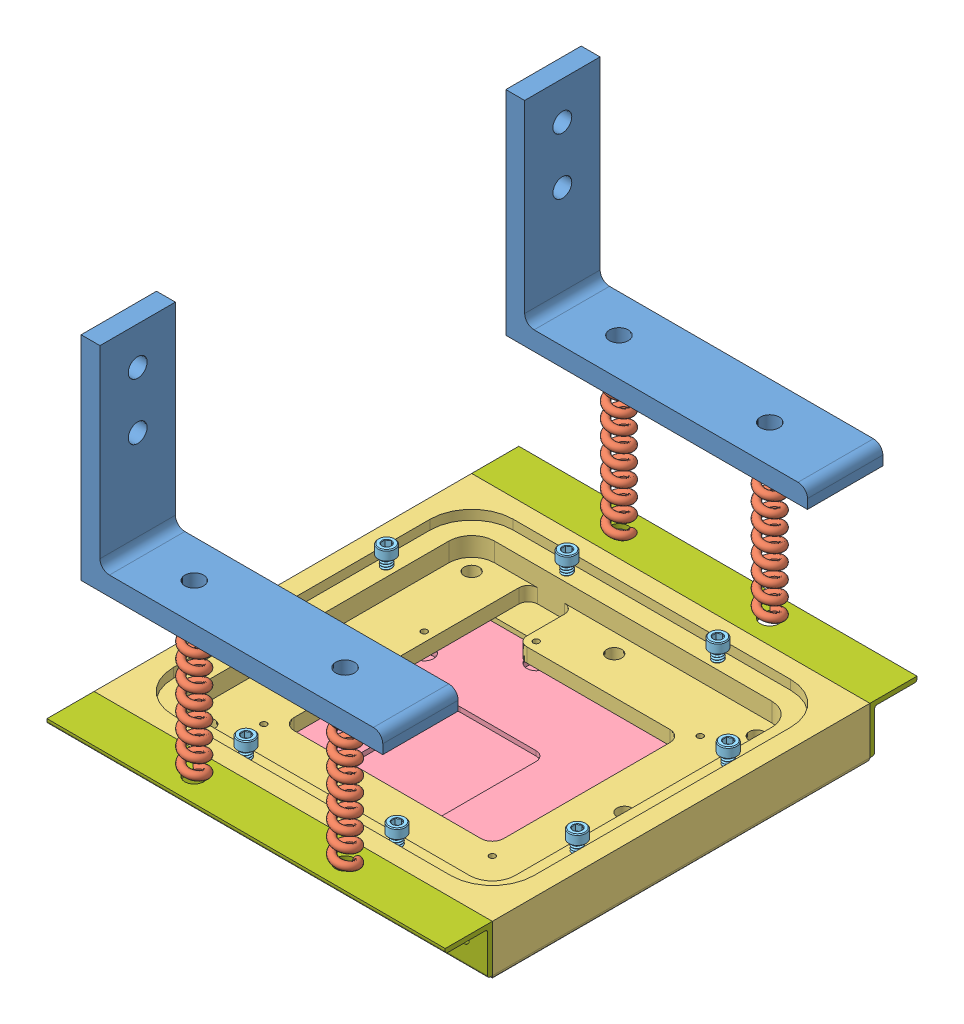
SolidWorks assembly SensorAssembly, configuration Default. Lengths in mm.
Overall size (134.11 141.53 168.43).
24 component instances, 8 part files, 20 mates.
Components (placement in the parent):
- Sensor Mount Bracket-1: Sensor Mount Bracket [8982K286] at (7.5304 42.6839 -62.5585) x (0 -1 0) z (0 0 1) size (71.68 101.6 25.4)
- Sensor Mount Bracket-2: Sensor Mount Bracket [8982K286] at (7.5304 42.6839 80.4689) x (0 -1 0) z (0 0 1) size (71.68 101.6 25.4)
- Rudimentary Spring-1: Rudimentary Spring [Default] at (32.9304 -46.2161 -62.5585) x (-0.173505 0 0.984833) z (-0.984833 0 -0.173505) size (9.2 55.29 9.2)
- Rudimentary Spring-2: Rudimentary Spring [Default] at (83.7304 -46.2161 -62.5585) x (0.992471 0 0.122483) z (-0.122483 0 0.992471) size (9.2 55.29 9.2)
- Rudimentary Spring-3: Rudimentary Spring [Default] at (32.9304 -46.2161 80.4689) size (9.2 55.29 9.2)
- Rudimentary Spring-4: Rudimentary Spring [Default] at (83.7304 -46.2161 80.4689) x (0.394048 0 0.91909) z (-0.91909 0 0.394048) size (9.2 55.29 9.2)
- NDE Sensor Mount Assembly-2: NDE Sensor Mount Assembly [Default] at (58.3304 -65.2661 8.9552) size (134.11 22.72 127.15)
  - CaseBody-1: CaseBody [Default] at origin size (134.11 17.46 127.15)
  - WearPlateAndMount-1: WearPlateAndMount [Default] at (0 3.175 0) size (108.71 3.17 101.75)
  - Cover Plate-1: Cover Plate [Default] at (0 15.875 0) size (121.41 3.17 114.45) (hidden)
  - 97334A146_NYLON SOCKET HEAD CAP SCREW-1: 97334A146_NYLON SOCKET HEAD CAP SCREW [97334A146] at (-57.531 9.525 -25.4) x (1 0 0) z (0 -1 0) size (5.74 5.74 13.88)
  - 97334A146_NYLON SOCKET HEAD CAP SCREW-2: 97334A146_NYLON SOCKET HEAD CAP SCREW [97334A146] at (-57.531 9.525 25.4) x (1 0 0) z (0 -1 0) size (5.74 5.74 13.88)
  - 97334A146_NYLON SOCKET HEAD CAP SCREW-3: 97334A146_NYLON SOCKET HEAD CAP SCREW [97334A146] at (-25.4 9.525 54.0512) x (1 0 0) z (0 -1 0) size (5.74 5.74 13.88)
  - 97334A146_NYLON SOCKET HEAD CAP SCREW-4: 97334A146_NYLON SOCKET HEAD CAP SCREW [97334A146] at (-25.4 9.525 -54.0512) x (1 0 0) z (0 -1 0) size (5.74 5.74 13.88)
  - 97334A146_NYLON SOCKET HEAD CAP SCREW-5: 97334A146_NYLON SOCKET HEAD CAP SCREW [97334A146] at (25.4 9.525 -54.0512) x (1 0 0) z (0 -1 0) size (5.74 5.74 13.88)
  - 97334A146_NYLON SOCKET HEAD CAP SCREW-6: 97334A146_NYLON SOCKET HEAD CAP SCREW [97334A146] at (25.4 9.525 54.0512) x (1 0 0) z (0 -1 0) size (5.74 5.74 13.88)
  - 97334A146_NYLON SOCKET HEAD CAP SCREW-7: 97334A146_NYLON SOCKET HEAD CAP SCREW [97334A146] at (57.531 9.525 -25.4) x (1 0 0) z (0 -1 0) size (5.74 5.74 13.88)
  - 97334A146_NYLON SOCKET HEAD CAP SCREW-8: 97334A146_NYLON SOCKET HEAD CAP SCREW [97334A146] at (57.531 9.525 25.4) x (1 0 0) z (0 -1 0) size (5.74 5.74 13.88)
- 97164A111_TAPEARED HEAT-SET INSERTS FOR PLASTIC -1: 97164A111_TAPEARED HEAT-SET INSERTS FOR PLASTIC  [97164A111] at (-0.7881 -54.1536 68.7214) x (1 0 0) z (0 -1 0) size (5.6 7.12 5.61)
- 97164A111_TAPEARED HEAT-SET INSERTS FOR PLASTIC -2: 97164A111_TAPEARED HEAT-SET INSERTS FOR PLASTIC  [97164A111] at (117.4489 -54.1536 68.7214) x (1 0 0) z (0 -1 0) size (5.6 7.12 5.61)
- 97164A111_TAPEARED HEAT-SET INSERTS FOR PLASTIC -3: 97164A111_TAPEARED HEAT-SET INSERTS FOR PLASTIC  [97164A111] at (-0.7881 -54.1536 -50.811) x (-0.923728 -0.383049 0) z (0.383049 -0.923728 0) size (5.6 7.12 5.61)
- 97164A111_TAPEARED HEAT-SET INSERTS FOR PLASTIC -4: 97164A111_TAPEARED HEAT-SET INSERTS FOR PLASTIC  [97164A111] at (117.4489 -54.1536 -50.811) x (-0.923728 -0.383049 0) z (0.383049 -0.923728 0) size (5.6 7.12 5.61)
- 8982K511_MULTIPURPOSE 6061 ALUMINUM 90 DEGREE ANGLE (1)-1: 8982K511_MULTIPURPOSE 6061 ALUMINUM 90 DEGREE ANGLE (1) [8982K511] at (58.3304 -54.1536 -54.621) x (0 1 0) z (-1 0 0) size (15.88 15.88 134.11)
- 8982K511_MULTIPURPOSE 6061 ALUMINUM 90 DEGREE ANGLE (1)-4: 8982K511_MULTIPURPOSE 6061 ALUMINUM 90 DEGREE ANGLE (1) [8982K511] at (58.3304 -54.1536 72.5314) x (0 1 0) z (1 0 0) size (15.88 15.88 134.11)
Mates (geometry in assembly coordinates):
- Coincident18: coincident anti-aligned: plane of Revised NDE Sensor Mount-1/CaseBody-1 through (-0.7881 -54.1536 66.1814) normal (0 0 1); plane of 97164A111_TAPEARED HEAT-SET INSERTS FOR PLASTIC -1 through (1.2947 -54.1536 66.1814) normal (0 0 -1)
- Concentric7: concentric aligned: circle of Revised NDE Sensor Mount-1/CaseBody-1; circle of 97164A111_TAPEARED HEAT-SET INSERTS FOR PLASTIC -1
- Coincident19: coincident anti-aligned: plane of Revised NDE Sensor Mount-1/CaseBody-1 through (-0.7881 -54.1536 -48.271) normal (0 0 -1); plane of 97164A111_TAPEARED HEAT-SET INSERTS FOR PLASTIC -3 through (-2.712 -54.9514 -48.271) normal (0 0 1)
- Concentric8: concentric aligned: cylinder of Revised NDE Sensor Mount-1/CaseBody-1 through (-0.7881 -54.1536 -48.271) axis (0 0 -1) radius 2.3495; circle of 97164A111_TAPEARED HEAT-SET INSERTS FOR PLASTIC -3
- Coincident20: coincident anti-aligned: plane of Revised NDE Sensor Mount-1/CaseBody-1 through (117.4489 -54.1536 -48.271) normal (0 0 -1); plane of 97164A111_TAPEARED HEAT-SET INSERTS FOR PLASTIC -4 through (115.525 -54.9514 -48.271) normal (0 0 1)
- Concentric9: concentric aligned: cylinder of Revised NDE Sensor Mount-1/CaseBody-1 through (117.4489 -54.1536 -48.271) axis (0 0 -1) radius 2.3495; circle of 97164A111_TAPEARED HEAT-SET INSERTS FOR PLASTIC -4
- Coincident21: coincident anti-aligned: plane of Revised NDE Sensor Mount-1/CaseBody-1 through (117.4489 -54.1536 66.1814) normal (0 0 1); plane of 97164A111_TAPEARED HEAT-SET INSERTS FOR PLASTIC -2 through (119.5317 -54.1536 66.1814) normal (0 0 -1)
- Concentric10: concentric aligned: cylinder of Revised NDE Sensor Mount-1/CaseBody-1 through (117.4489 -54.1536 66.1814) axis (0 0 1) radius 2.3495; circle of 97164A111_TAPEARED HEAT-SET INSERTS FOR PLASTIC -2
- Coincident26: coincident anti-aligned: plane of Sensor Mount Bracket-1 through (7.5304 4.5839 -49.8585) normal (0 -1 0); plane of Rudimentary Spring-1 through (28.0351 4.5839 -68.0936) normal (0 1 0)
- Coincident27: coincident anti-aligned: plane of Sensor Mount Bracket-2 through (7.5304 4.5839 93.1689) normal (0 -1 0); plane of Rudimentary Spring-3 through (28.3286 4.5839 86.2504) normal (0 1 0)
- Concentric17: concentric anti-aligned: cylinder of Sensor Mount Bracket-1 through (83.7304 80.7849 -62.5585) axis (0 -1 0) radius 3.175; cylinder of Rudimentary Spring-2 through (83.7304 -48.6775 -62.5585) axis (0 1 0) radius 2.019
- Concentric18: concentric anti-aligned: cylinder of Sensor Mount Bracket-2 through (83.7304 80.7849 80.4689) axis (0 -1 0) radius 3.175; cylinder of Rudimentary Spring-4 through (83.7304 -48.6775 80.4689) axis (0 1 0) radius 2.019
- Concentric19: concentric anti-aligned: cylinder of Sensor Mount Bracket-1 through (32.9304 80.7849 -62.5585) axis (0 -1 0) radius 3.175; cylinder of Rudimentary Spring-1 through (32.9304 -48.6775 -62.5585) axis (0 1 0) radius 2.019
- Concentric20: concentric anti-aligned: cylinder of Sensor Mount Bracket-2 through (32.9304 80.7849 80.4689) axis (0 -1 0) radius 3.175; cylinder of Rudimentary Spring-3 through (32.9304 -48.6775 80.4689) axis (0 1 0) radius 2.019
- Coincident28: coincident anti-aligned: plane of NDE Sensor Mount Assembly-2/CaseBody-1 through (58.3304 -49.3911 -54.621) normal (0 0 -1); plane of 8982K511_MULTIPURPOSE 6061 ALUMINUM 90 DEGREE ANGLE (1)-1 through (-8.7256 -62.0911 -54.621) normal (0 0 1)
- Coincident29: coincident aligned: plane of NDE Sensor Mount Assembly-2/CaseBody-1 through (-8.7256 -49.3911 8.9552) normal (-1 0 0); plane of 8982K511_MULTIPURPOSE 6061 ALUMINUM 90 DEGREE ANGLE (1)-1 through (-8.7256 -47.0098 -69.7022) normal (-1 0 0)
- Coincident30: coincident aligned: plane of NDE Sensor Mount Assembly-2/CaseBody-1 through (58.3304 -46.2161 8.9552) normal (0 1 0); plane of 8982K511_MULTIPURPOSE 6061 ALUMINUM 90 DEGREE ANGLE (1)-1 through (-8.7256 -46.2161 -54.621) normal (0 1 0)
- Coincident31: coincident anti-aligned: plane of NDE Sensor Mount Assembly-2/CaseBody-1 through (58.3304 -49.3911 72.5314) normal (0 0 1); plane of 8982K511_MULTIPURPOSE 6061 ALUMINUM 90 DEGREE ANGLE (1)-4 through (125.3864 -62.0911 72.5314) normal (0 0 -1)
- Coincident32: coincident aligned: plane of NDE Sensor Mount Assembly-2/CaseBody-1 through (-8.7256 -49.3911 8.9552) normal (-1 0 0); plane of 8982K511_MULTIPURPOSE 6061 ALUMINUM 90 DEGREE ANGLE (1)-4 through (-8.7256 -47.0098 87.6127) normal (-1 0 0)
- Coincident33: coincident aligned: plane of NDE Sensor Mount Assembly-2/CaseBody-1 through (58.3304 -46.2161 8.9552) normal (0 1 0); plane of 8982K511_MULTIPURPOSE 6061 ALUMINUM 90 DEGREE ANGLE (1)-4 through (125.3864 -46.2161 72.5314) normal (0 1 0)
